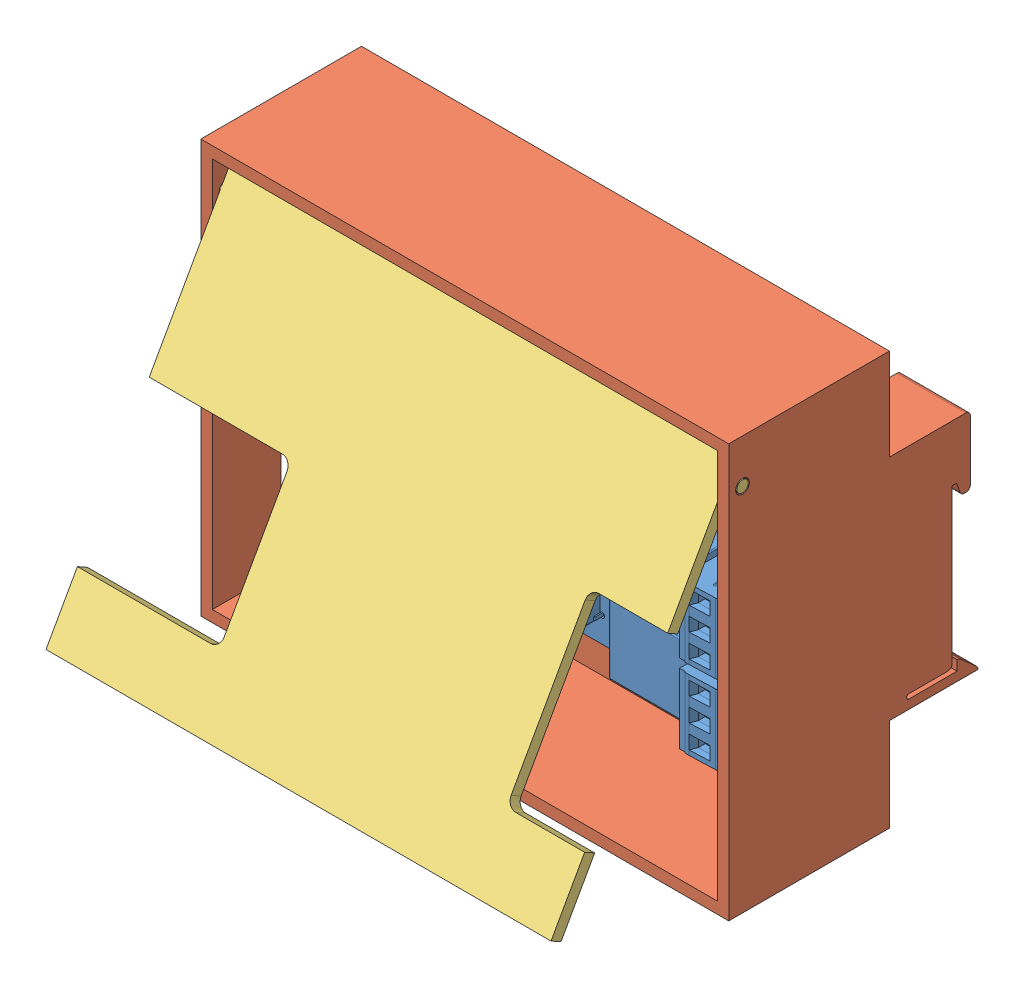
SolidWorks assembly Ensamblaje1, configuration Predeterminado. Lengths in mm.
Overall size (115 90 90.51).
3 component instances, 3 part files, 7 mates.
Components (placement in the parent):
- powermike-1: powermike [Predeterminado] at (-286.4645 123.3018 -9.8485) size (107.74 70.14 26.4)
- caja-1: caja [Predeterminado] at (-78.9645 -1.4082 -14.8485) x (0 0 1) z (-1 0 0) size (54.29 90 115)
- tapa-1: tapa [Predeterminado] at (-81.4645 -9.8548 54.1899) x (1 0 0) z (0 -0.872378 0.488831) size (115 2.5 84)
Mates (geometry in assembly coordinates):
- Concéntrica1: concentric anti-aligned: circle of powermike-1; circle of Pieza4-1
- Concéntrica2: concentric anti-aligned: cylinder of Pieza4-1 through (-193.9646 58.8018 17.1515) axis (1 0 0) radius 1.5; cylinder of tapa-1 through (-78.9645 58.8018 17.1515) axis (-1 0 0) radius 1.25
- Coincidente2: coincident anti-aligned: plane of Pieza4-1 through (-81.4645 65.8018 20.1515) normal (-1 0 0); plane of tapa-1 through (-81.4645 -8.6327 56.3708) normal (1 0 0)
- Concéntrica4: concentric anti-aligned: circle of powermike-1; circle of Pieza4-1
- Concéntrica5: concentric anti-aligned: circle of powermike-1; circle of Pieza4-1
- Concéntrica6: concentric anti-aligned: circle of powermike-1; circle of Pieza4-1
- Coincidente3: coincident anti-aligned: plane of powermike-1 through (-136.4645 23.3018 -9.8485) normal (0 0 -1); plane of Pieza4-1 through (-78.9645 -1.4082 -9.8485) normal (0 0 1)
